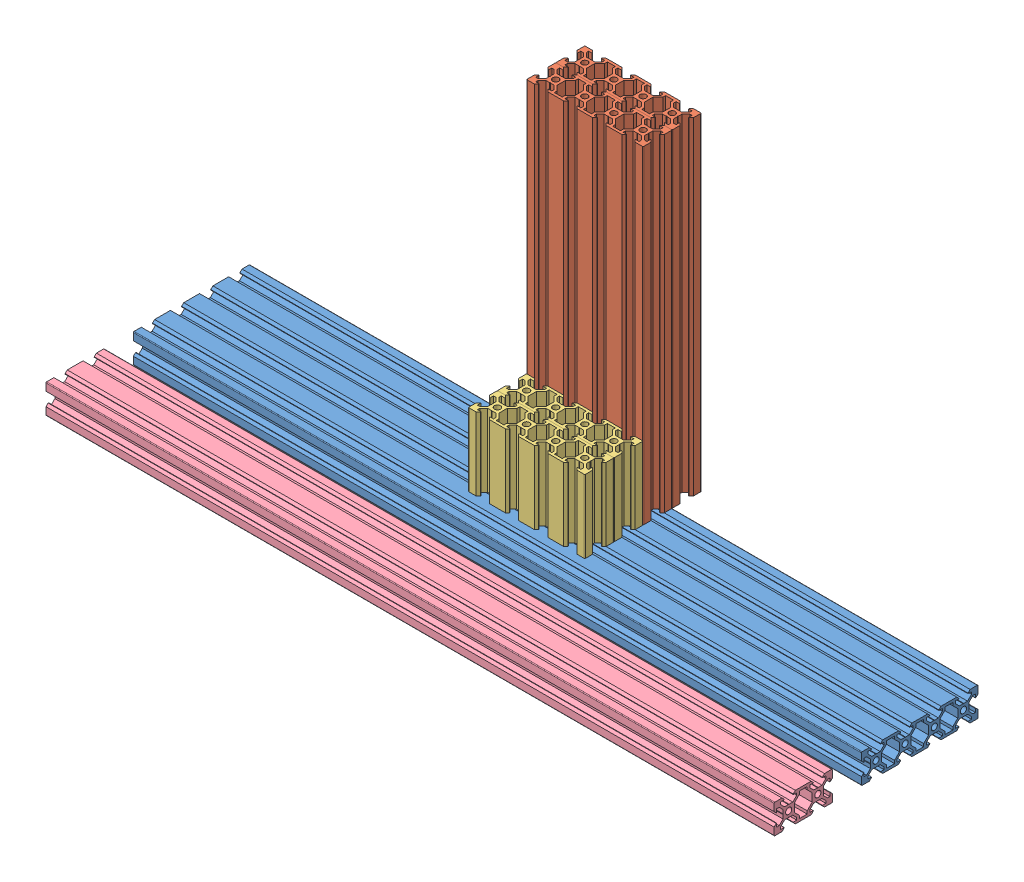
SolidWorks assembly Aluminum Extrusion Frame, configuration Default. Lengths in mm.
Overall size (500 245 160).
6 component instances, 4 part files, 18 mates.
Components (placement in the parent):
- V-Slot 20x80x500 Linear Rail-1: V-Slot 20x80x500 Linear Rail [Default] at (250 10 150.034) x (0 -1 0) z (-1 0 0) size (20 80 500)
- V-Slot 20x80x225 Linear Rail-2: V-Slot 20x80x225 Linear Rail [Default] at (0 245 100.034) x (0 0 1) z (0 -1 0) size (20 80 225)
- V-Slot 20x80x225 Linear Rail-3: V-Slot 20x80x225 Linear Rail [Default] at (0 245 120.034) x (0 0 1) z (0 -1 0) size (20 80 225)
- V-Slot 20x80x50 Linear Rail-4: V-Slot 20x80x50 Linear Rail [Default] at (0 70 140.034) x (0 0 1) z (0 -1 0) size (20 80 50)
- V-Slot 20x40x500 Linear Rail-1: V-Slot 20x40x500 Linear Rail [Default] at (250 10 230.034) x (0 1 0) z (-1 0 0) size (20 40 500)
- V-Slot 20x80x50 Linear Rail-5: V-Slot 20x80x50 Linear Rail [Default] at (0 70 160.034) x (0 0 1) z (0 -1 0) size (20 80 50)
Mates (geometry in assembly coordinates):
- Coincident1: coincident anti-aligned: plane of V-Slot 20x80x500 Linear Rail-1 through (-250 0 150.034) normal (0 -1 0)
- Parallel1: parallel anti-aligned: plane of V-Slot 20x80x500 Linear Rail-1 through (250 10 150.034) normal (-1 0 0)
- Symmetric1: symmetric aligned: plane of V-Slot 20x80x500 Linear Rail-1 through (-250 10 150.034) normal (-1 0 0); plane of V-Slot 20x80x500 Linear Rail-1 through (250 10 150.034) normal (1 0 0)
- Coincident3: coincident anti-aligned: plane of V-Slot 20x80x500 Linear Rail-1 through (-250 20 150.034) normal (0 1 0); plane of V-Slot 20x80x225 Linear Rail-2 through (0 20 100.034) normal (0 -1 0)
- Width1: width anti-aligned: plane of V-Slot 20x80x225 Linear Rail-2 through (-40 20 100.034) normal (-1 0 0); plane of V-Slot 20x80x225 Linear Rail-2 through (40 20 100.034) normal (1 0 0); plane of V-Slot 20x80x500 Linear Rail-1 through (250 10 150.034) normal (1 0 0); plane of V-Slot 20x80x500 Linear Rail-1 through (-250 10 150.034) normal (-1 0 0)
- Coincident5: coincident anti-aligned: plane of V-Slot 20x80x500 Linear Rail-1 through (-250 20 150.034) normal (0 1 0); plane of V-Slot 20x80x225 Linear Rail-3 through (0 20 120.034) normal (0 -1 0)
- Width2: width anti-aligned: plane of V-Slot 20x80x225 Linear Rail-3 through (-40 20 120.034) normal (-1 0 0); plane of V-Slot 20x80x225 Linear Rail-3 through (40 20 120.034) normal (1 0 0); plane of V-Slot 20x80x500 Linear Rail-1 through (250 10 150.034) normal (1 0 0); plane of V-Slot 20x80x500 Linear Rail-1 through (-250 10 150.034) normal (-1 0 0)
- Coincident6: coincident anti-aligned: plane of V-Slot 20x80x225 Linear Rail-2 through (0 20 110.034) normal (0 0 1); plane of V-Slot 20x80x225 Linear Rail-3 through (0 20 110.034) normal (0 0 -1)
- Coincident7: coincident anti-aligned: plane of V-Slot 20x80x500 Linear Rail-1 through (-250 20 150.034) normal (0 1 0); plane of V-Slot 20x80x50 Linear Rail-4 through (0 20 140.034) normal (0 -1 0)
- Width3: width anti-aligned: plane of V-Slot 20x80x50 Linear Rail-4 through (-40 20 140.034) normal (-1 0 0); plane of V-Slot 20x80x50 Linear Rail-4 through (40 20 140.034) normal (1 0 0); plane of V-Slot 20x80x500 Linear Rail-1 through (250 10 150.034) normal (1 0 0); plane of V-Slot 20x80x500 Linear Rail-1 through (-250 10 150.034) normal (-1 0 0)
- Coincident8: coincident anti-aligned: plane of V-Slot 20x80x225 Linear Rail-3 through (0 20 130.034) normal (0 0 1); plane of V-Slot 20x80x50 Linear Rail-4 through (0 20 130.034) normal (0 0 -1)
- Distance2: distance = 20 mm anti-aligned: plane of V-Slot 20x40x500 Linear Rail-1 through (-250 10 210.034) normal (0 0 -1); plane of V-Slot 20x80x500 Linear Rail-1 through (-250 10 190.034) normal (0 0 1)
- Coincident13: coincident aligned: plane of V-Slot 20x80x500 Linear Rail-1 through (-250 20 150.034) normal (0 1 0); plane of V-Slot 20x40x500 Linear Rail-1 through (-250 20 230.034) normal (0 1 0)
- Coincident14: coincident aligned: plane of V-Slot 20x80x500 Linear Rail-1 through (250 10 150.034) normal (1 0 0); plane of V-Slot 20x40x500 Linear Rail-1 through (250 10 230.034) normal (1 0 0)
- Coincident16: coincident aligned: plane of V-Slot 20x80x500 Linear Rail-1 through (-250 10 110.034) normal (0 0 -1); plane of V-Slot 20x80x225 Linear Rail-3 through (0 20 110.034) normal (0 0 -1)
- Coincident17: coincident anti-aligned: plane of V-Slot 20x80x500 Linear Rail-1 through (-250 20 150.034) normal (0 1 0); plane of V-Slot 20x80x50 Linear Rail-5 through (0 20 160.034) normal (0 -1 0)
- Width4: width anti-aligned: plane of V-Slot 20x80x50 Linear Rail-5 through (-40 20 160.034) normal (-1 0 0); plane of V-Slot 20x80x50 Linear Rail-5 through (40 20 160.034) normal (1 0 0); plane of V-Slot 20x80x500 Linear Rail-1 through (250 10 150.034) normal (1 0 0); plane of V-Slot 20x80x500 Linear Rail-1 through (-250 10 150.034) normal (-1 0 0)
- Coincident18: coincident anti-aligned: plane of V-Slot 20x80x50 Linear Rail-4 through (0 20 150.034) normal (0 0 1); plane of V-Slot 20x80x50 Linear Rail-5 through (0 20 150.034) normal (0 0 -1)
